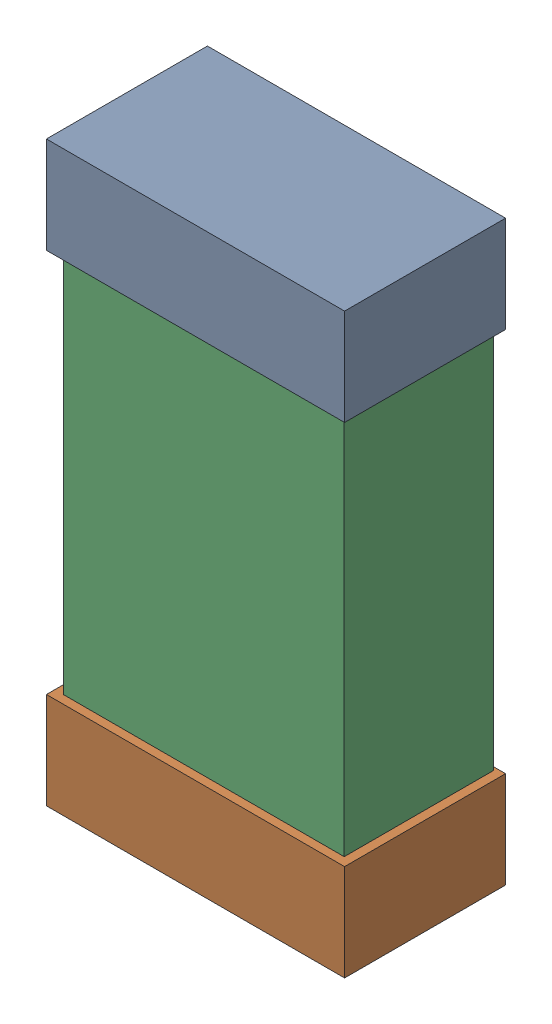
SolidWorks assembly R44, configuration Default. Lengths in mm.
Overall size (0.85 1.65 0.46).
6 component instances, 2 part files, 0 mates.
Components (placement in the parent):
- 432138512_16-1: 432138512_16 [Default] at (41.5501 52.3359 -0.8715) size (0.85 0.28 0.46)
  - Extruded-1: Extruded [Default] at origin size (0.85 0.28 0.46)
- 432138512_17-1: 432138512_17 [Default] at (41.5501 50.9643 -0.8715) size (0.85 0.28 0.46)
  - Extruded-1: Extruded [Default] at origin size (0.85 0.28 0.46)
- 432124816_8-1: 432124816_8 [Default] at (41.5501 51.6501 -0.8615) size (0.8 1.5 0.42)
  - Extruded (1)-1: Extruded (1) [Default] at origin size (0.8 1.5 0.42)
